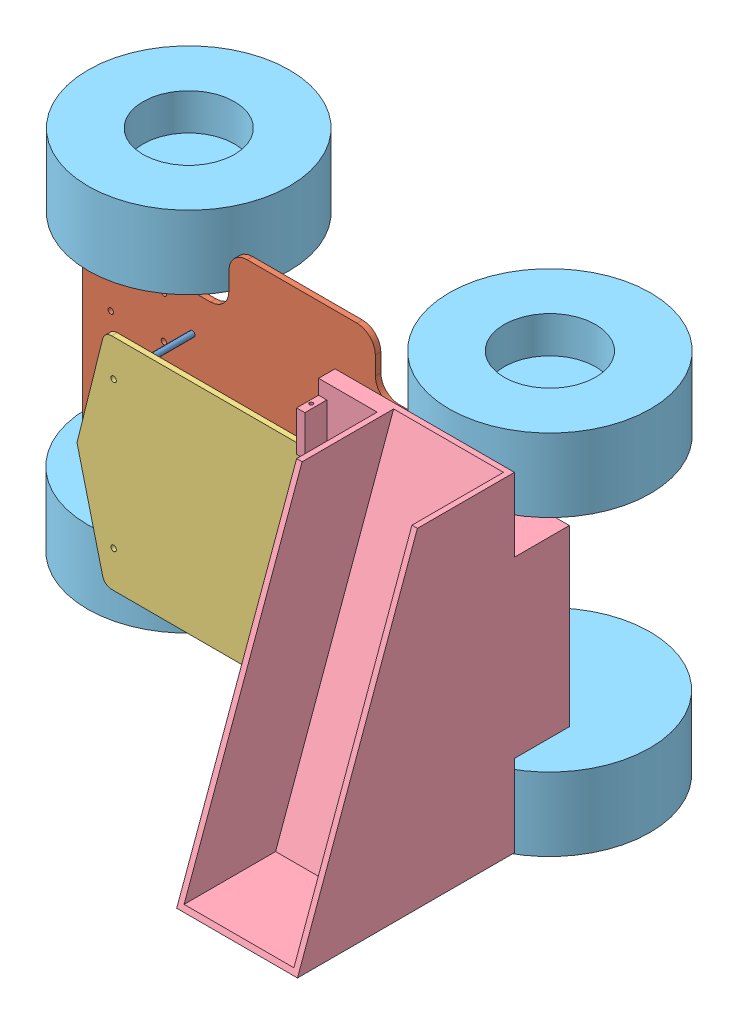
SolidWorks assembly assembly, configuration 預設. Lengths in mm.
Overall size (314.37 200 239.87).
11 component instances, 5 part files, 11 mates.
Components (placement in the parent):
- column-1: column [預設] at (-197.8223 83.6637 116.5) x (-0.923728 -0.383049 0) z (0 0 -1) size (3 3 40)
- plane-1: plane [預設] at (-257.8223 -46.3363 73.5) size (240 180 3)
- plane2-1: plane2 [預設] at (-217.8223 -16.3363 116.5) size (160 120 3)
- column-2: column [預設] at (-77.8223 83.6637 116.5) x (-0.923728 -0.383049 0) z (0 0 -1) size (3 3 40)
- column-3: column [預設] at (-197.8223 3.6637 116.5) x (-0.923728 -0.383049 0) z (0 0 -1) size (3 3 40)
- column-4: column [預設] at (-77.8223 3.6637 116.5) x (-0.923728 -0.383049 0) z (0 0 -1) size (3 3 40)
- slope-1: slope [預設] at (-57.8223 136.0752 106.5) x (0 -1 0) z (0 0 1) size (180 98 148.51)
- 車輪(模擬)-1: 車輪(模擬) [預設] at (-236.141 -56.3363 40.4561) x (1 0 0) z (0 1 0) size (110 110 40)
- 車輪(模擬)-2: 車輪(模擬) [預設] at (-31.7746 -56.3363 47.4881) x (1 0 0) z (0 1 0) size (110 110 40)
- 車輪(模擬)-3: 車輪(模擬) [預設] at (-236.1116 143.6637 40.1413) x (1 0 0) z (0 -1 0) size (110 110 40)
- 車輪(模擬)-4: 車輪(模擬) [預設] at (-32.0273 143.6637 46.931) x (1 0 0) z (0 -1 0) size (110 110 40)
Mates (geometry in assembly coordinates):
- 重合/共線/共點2: coincident anti-aligned: circle of column-1; circle of plane-1
- 重合/共線/共點4: coincident anti-aligned: circle of plane-1; circle of column-3
- 重合/共線/共點6: coincident anti-aligned: circle of column-1; circle of plane2-1
- 重合/共線/共點8: coincident anti-aligned: plane of plane-1 through (-257.8223 -46.3363 76.5) normal (0 0 1); plane of slope-1 through (-57.8223 136.0752 76.5) normal (0 0 -1)
- 重合/共線/共點9: coincident anti-aligned: plane of plane2-1 through (-57.8223 103.6637 119.5) normal (1 0 0); plane of slope-1 through (-57.8223 136.0752 109.5) normal (-1 0 0)
- 重合/共線/共點11: coincident anti-aligned: circle of plane-1; circle of column-4
- 重合/共線/共點12: coincident anti-aligned: circle of plane2-1; circle of column-4
- 重合/共線/共點13: coincident anti-aligned: plane of plane-1 through (-177.8223 -16.3363 76.5) normal (0 -1 0); plane of 車輪(模擬)-1 through (-236.141 -16.3363 40.4561) normal (0 1 0)
- 重合/共線/共點14: coincident anti-aligned: plane of plane-1 through (-97.8223 -16.3363 76.5) normal (0 -1 0); plane of 車輪(模擬)-2 through (-31.7746 -16.3363 47.4881) normal (0 1 0)
- 重合/共線/共點15: coincident anti-aligned: plane of plane-1 through (-177.8223 103.6637 76.5) normal (0 1 0); plane of 車輪(模擬)-3 through (-236.1116 103.6637 40.1413) normal (0 -1 0)
- 重合/共線/共點16: coincident anti-aligned: plane of plane-1 through (-97.8223 103.6637 76.5) normal (0 1 0); plane of 車輪(模擬)-4 through (-32.0273 103.6637 46.931) normal (0 -1 0)
